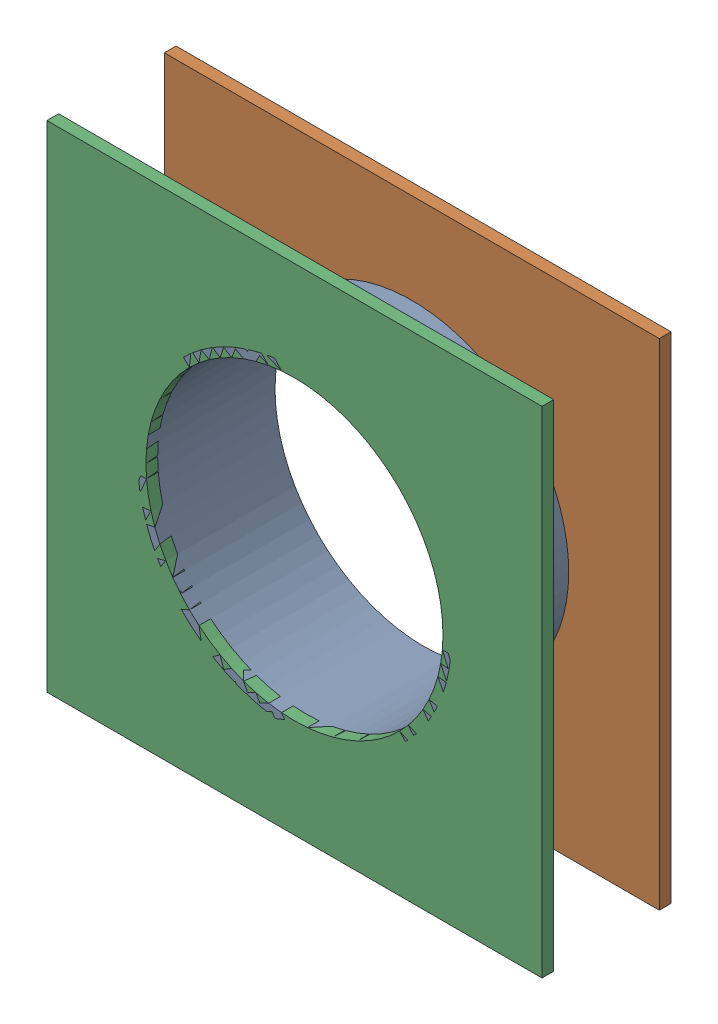
SolidWorks assembly Pad SWD-1(12.954mm,48.387mm) on Multi-Layer, configuration Predeterminado. Lengths in mm.
Overall size (1.5 1.5 0.39).
6 component instances, 3 part files, 0 mates.
Components (placement in the parent):
- Pad Hole-1-1: Pad Hole-1 [Predeterminado] at (12.954 48.387 -0.4013) size (0.95 0.95 0.39)
  - Pad Hole-Part-1-1-1: Pad Hole-Part-1-1 [Predeterminado] at origin size (0.95 0.95 0.39)
- Pad Copper-1: Pad Copper [Predeterminado] at (-68.317 -44.187 -0.4013) size (1.5 1.5 0.04)
  - Pad Copper-Part-1-1: Pad Copper-Part-1 [Predeterminado] at origin size (1.5 1.5 0.04)
- Pad Copper-1-1: Pad Copper-1 [Predeterminado] at (-68.317 -44.187 -0.0457) size (1.5 1.5 0.04)
  - Pad Copper-Part-1-1-1: Pad Copper-Part-1-1 [Predeterminado] at origin size (1.5 1.5 0.04)
